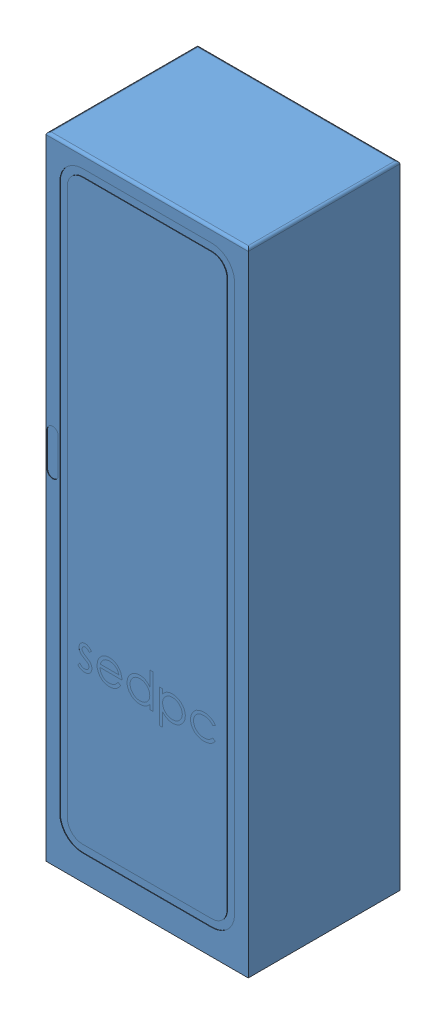
SolidWorks assembly GAINETE - INTERIOR FO ROUR, configuration Predeterminado. Lengths in mm.
Overall size (800 2500 600).
7 component instances, 5 part files, 12 mates.
Components (placement in the parent):
- Gabinete SEDPC 5-1: Gabinete SEDPC 5 [Predeterminado] at (-907.2484 -1967.7598 2500) size (800 2500 600)
- DISTRIBUIDOR DE FIBRA OPTICA-1: DISTRIBUIDOR DE FIBRA OPTICA [Predeterminado] at (-907.2484 -505.6277 2562.2356) size (384.09 172.19 260.09)
- ROUTER CISCO-1: ROUTER CISCO [Predeterminado] at (-907.1669 -97.3964 2650.0663) size (525 78 408.81)
- Pieza2^GAINETE - INTERIOR FO ROUR-1: Pieza2^GAINETE - INTERIOR FO ROUR [Predeterminado] at (-907.2484 -1967.7598 2200) x (-1 0 0) z (0 0 -1) size (512.33 2007.46 498) (virtual)
- ROUTER CISCO-2: ROUTER CISCO [Predeterminado] at (-900.3305 81.3086 2650.0663) size (525 78 408.81)
- DISTRIBUIDOR DE FIBRA OPTICA-2: DISTRIBUIDOR DE FIBRA OPTICA [Predeterminado] at (-907.2484 -814.0815 2562.2356) size (384.09 172.19 260.09) (hidden)
- sampled values 55-2: sampled values 55 [Predeterminado] at (-907.6023 258.2476 2474.6848) x (-1 0 0) z (0 0 -1) size (620.63 268.25 292)
Mates (geometry in assembly coordinates):
- Ancho1: width aligned: plane of Gabinete SEDPC 5-1 through (-507.2484 532.2402 2200) normal (1 0 0); plane of Gabinete SEDPC 5-1 through (-1307.2484 532.2402 2200) normal (-1 0 0); plane of ROUTER CISCO-1 through (-644.7484 -59.9153 2337.7778) normal (1 0 0); plane of ROUTER CISCO-1 through (-1169.7484 -59.9153 2337.7778) normal (-1 0 0)
- Ancho2: width aligned: plane of Gabinete SEDPC 5-1 through (-507.2484 532.2402 2200) normal (1 0 0); plane of Gabinete SEDPC 5-1 through (-1307.2484 532.2402 2200) normal (-1 0 0); plane of DISTRIBUIDOR DE FIBRA OPTICA-1 through (-715.2037 -505.6277 2457.2356) normal (1 0 0); plane of DISTRIBUIDOR DE FIBRA OPTICA-1 through (-1099.293 -505.6277 2457.2356) normal (-1 0 0)
- EnPosición1: in place: plane of Gabinete SEDPC 5-1 through (-1307.2484 532.2402 2200) normal (0 0 -1); plane of ? through (0 0 2200) normal (0 0 -1); moOrthogonalPlaneRef_w of Gabinete SEDPC 5-1 through (-1307.2484 532.2402 2200) normal (0 0 -1); unknown of ?; plane of Gabinete SEDPC 5-1 through (-1307.2484 532.2402 2200) normal (0 0 -1); plane of ? through (0 0 2200) normal (-1 0 0); plane of Gabinete SEDPC 5-1 through (-1307.2484 532.2402 2200) normal (0 0 -1); unknown of Pieza2^GAINETE - INTERIOR FO ROUR-1
- Coincidente1: coincident aligned: plane of Gabinete SEDPC 5-1; plane of Pieza2^GAINETE - INTERIOR FO ROUR-1
- Coincidente2: coincident aligned: moOrthogonalPlaneRef_w of Gabinete SEDPC 5-1 through (-907.2484 -1967.7598 2200) normal (0 1 0); plane of Pieza2^GAINETE - INTERIOR FO ROUR-1
- Coincidente3: coincident anti-aligned: moOrthogonalPlaneRef_w of Gabinete SEDPC 5-1 through (-907.2484 -1967.7598 2200) normal (1 0 0); plane of Pieza2^GAINETE - INTERIOR FO ROUR-1 through (-907.2484 -1967.7598 2200) normal (-1 0 0)
- Coincidente4: coincident aligned: plane of ROUTER CISCO-1 through (-907.2484 -97.4153 2712.7778) normal (0 0 1); plane of ROUTER CISCO-2 through (-900.4119 81.2897 2712.7778) normal (0 0 1)
- Coincidente5: coincident aligned: plane of DISTRIBUIDOR DE FIBRA OPTICA-1 through (-907.2484 -575.6277 2687.2356) normal (0 0 1); plane of DISTRIBUIDOR DE FIBRA OPTICA-2 through (-907.2484 -814.0815 2687.2356) normal (0 0 1)
- Coincidente6: coincident aligned: plane of DISTRIBUIDOR DE FIBRA OPTICA-1 through (-715.2037 -575.6277 2457.2356) normal (1 0 0); plane of DISTRIBUIDOR DE FIBRA OPTICA-2 through (-715.2037 -884.0815 2457.2356) normal (1 0 0)
- Ancho3: width aligned: plane of Gabinete SEDPC 5-1 through (-507.2484 532.2402 2200) normal (1 0 0); plane of Gabinete SEDPC 5-1 through (-1307.2484 532.2402 2200) normal (-1 0 0); plane of sampled values 55-2 through (-597.2484 124.2402 2270) normal (1 0 0); plane of sampled values 55-2 through (-1217.2484 124.2402 2270) normal (-1 0 0)
- Distancia1: distance = 140 mm aligned: plane of Gabinete SEDPC 5-1 through (-907.2484 532.2402 2500) normal (0 1 0); plane of sampled values 55-2 through (-597.2484 392.2402 2270) normal (0 1 0)
- Distancia2: distance = 70 mm aligned: plane of Gabinete SEDPC 5-1 through (-1307.2484 532.2402 2200) normal (0 0 -1); plane of sampled values 55-2 through (-907.2484 258.2402 2270) normal (0 0 -1)
